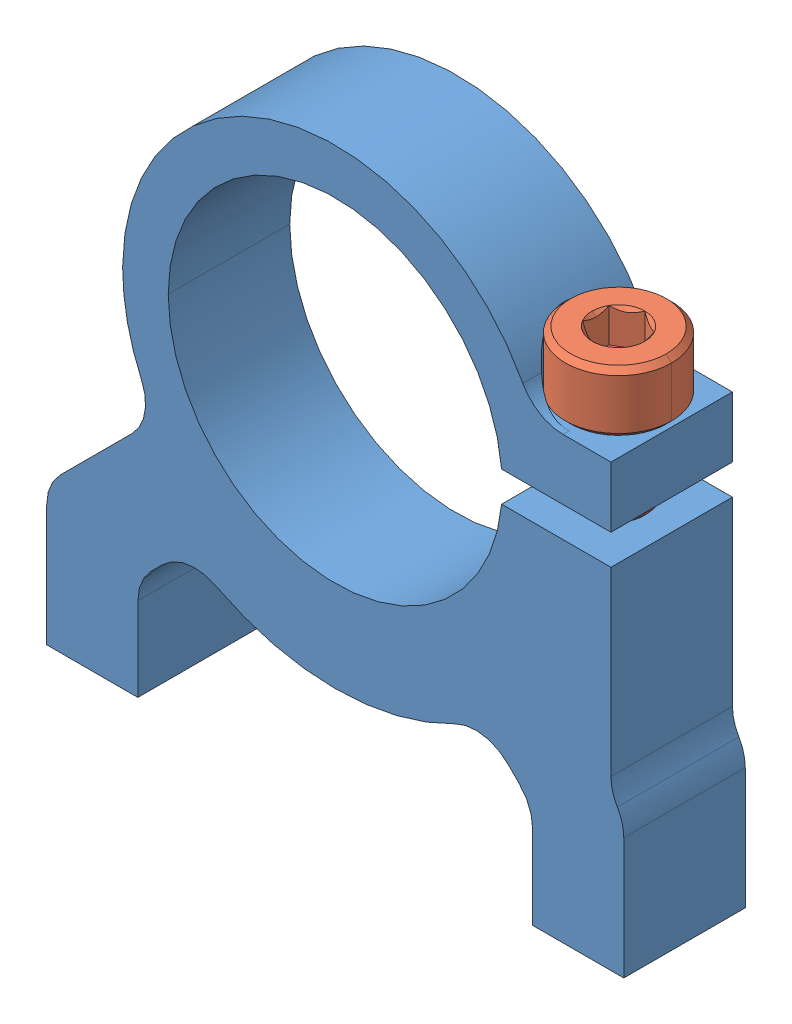
SolidWorks assembly 1-Side, 2-Post Clamping Mount (22mm Bore)1400-0032-0022, configuration Default. Lengths in mm.
Overall size (38 38 8).
2 component instances, 2 part files, 0 mates.
Components (placement in the parent):
- 1400-0032-0022.STEP-1: 1400-0032-0022.STEP [Default] at (-24.4657 26.139 -5.3669) size (38 38 8)
- 2800-0004-0010_90128A207.STEP-1: 2800-0004-0010_90128A207.STEP [Default] at (-9.8113 21.139 -1.3669) x (1 0 0) z (0 -1 0) size (7 7 14.01)
